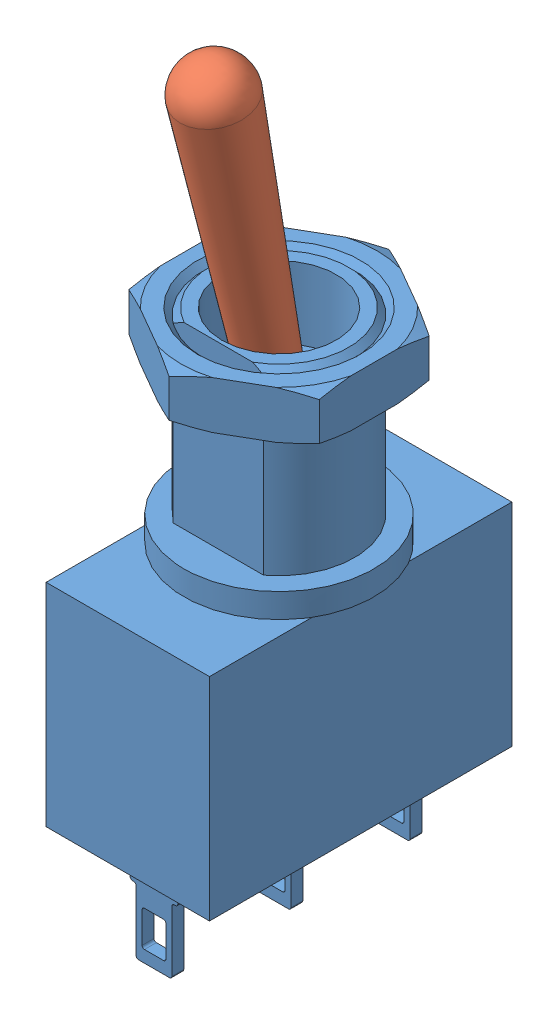
SolidWorks assembly Panel Mount SPDT, configuration Default. Lengths in mm.
Overall size (8 32.25 12.7).
2 component instances, 2 part files, 3 mates.
Components (placement in the parent):
- Panel Mount SPDT Base-1: Panel Mount SPDT Base [Default] at (16.9151 4.9885 6.5277) size (8 21.43 12.7)
- Panel Mount SPDT Arm-1: Panel Mount SPDT Arm [Default] at (16.9151 31.5016 9.2551) x (1 0 0) z (0 -0.207912 0.978148) size (3 15.7 3)
Mates (geometry in assembly coordinates):
- Concentric1: concentric: sphere of Panel Mount SPDT Base-1; sphere of Panel Mount SPDT Arm-1
- Coincident2: coincident aligned: plane of Panel Mount SPDT Base-1 through (16.9151 4.9885 6.5277) normal (1 0 0); plane of Panel Mount SPDT Arm-1
- LimitAngle1: limit planar angle = 0.20944 rad aligned: line of Panel Mount SPDT Base-1 through (16.9151 23.49 6.5277) axis (0 -1 0); line of Panel Mount SPDT Arm-1 through (16.9151 33.6973 9.7218) axis (0 -0.978148 -0.207912)
